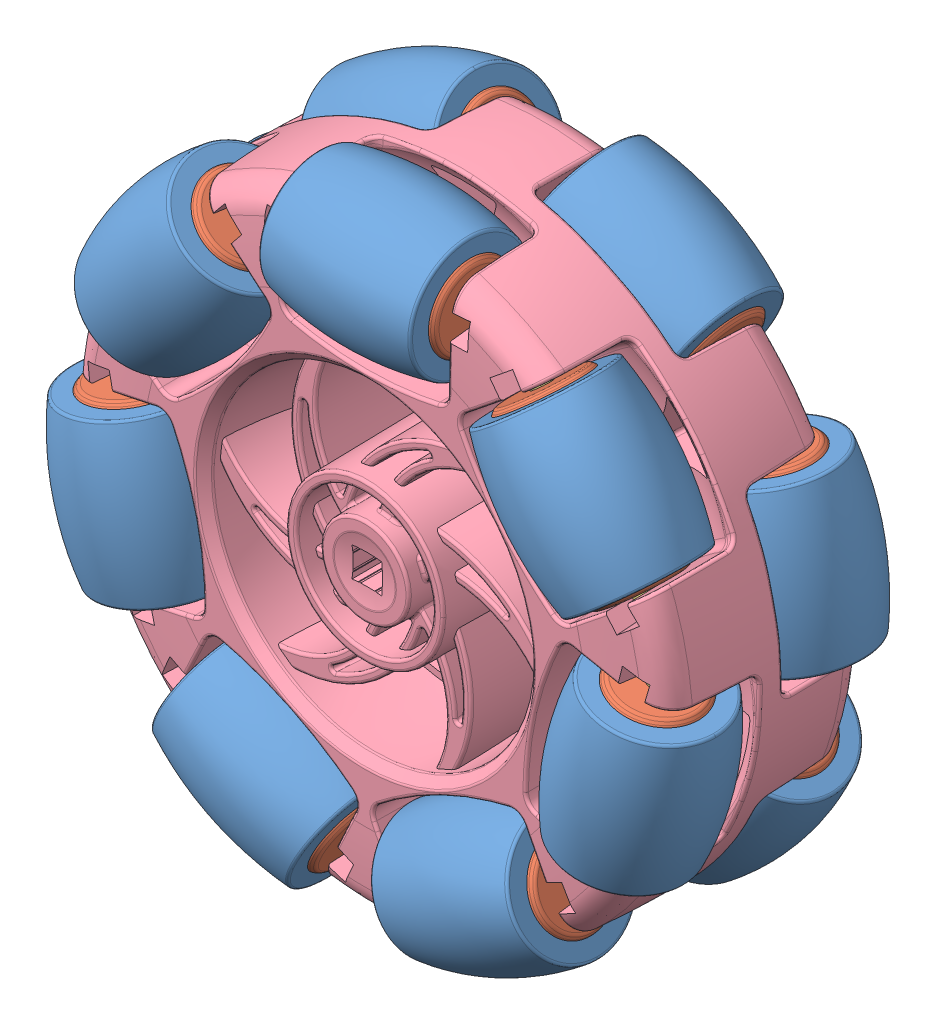
SolidWorks assembly 276-1902, configuration Default. Lengths in mm.
Overall size (73.36 73.05 31).
57 component instances, 4 part files, 0 mates.
Components (placement in the parent):
- ASM-SMALL-WHEEL_ASM-1: ASM-SMALL-WHEEL_ASM [Default] at (0 0 8) size (23 15 15)
  - SMALL-RUBBER-WHEEL-1: SMALL-RUBBER-WHEEL [Default] at origin size (16.5 15 15)
  - SMALL-HUB-1: SMALL-HUB [Default] at (0 27.5 0) size (17.5 10.2 10.2)
  - SMALL-WHEEL-AXIS-1: SMALL-WHEEL-AXIS [Default] at (0 27.5 0) x (0 1 0) z (1 0 0) size (2 2 23)
- ASM-SMALL-WHEEL_ASM-2: ASM-SMALL-WHEEL_ASM [Default] at (0 0 8) x (-0.222399 -0.974956 0) z (0 0 1) size (23 15 15)
  - SMALL-RUBBER-WHEEL-1: SMALL-RUBBER-WHEEL [Default] at origin size (16.5 15 15)
  - SMALL-HUB-1: SMALL-HUB [Default] at (0 27.5 0) size (17.5 10.2 10.2)
  - SMALL-WHEEL-AXIS-1: SMALL-WHEEL-AXIS [Default] at (0 27.5 0) x (0 1 0) z (1 0 0) size (2 2 23)
- ASM-SMALL-WHEEL_ASM-3: ASM-SMALL-WHEEL_ASM [Default] at (0 0 8) x (-0.900926 -0.433974 0) z (0 0 1) size (23 15 15)
  - SMALL-RUBBER-WHEEL-1: SMALL-RUBBER-WHEEL [Default] at origin size (16.5 15 15)
  - SMALL-HUB-1: SMALL-HUB [Default] at (0 27.5 0) size (17.5 10.2 10.2)
  - SMALL-WHEEL-AXIS-1: SMALL-WHEEL-AXIS [Default] at (0 27.5 0) x (0 1 0) z (1 0 0) size (2 2 23)
- ASM-SMALL-WHEEL_ASM-4: ASM-SMALL-WHEEL_ASM [Default] at (0 0 8) x (0.623607 -0.781738 0) z (0 0 1) size (23 15 15)
  - SMALL-RUBBER-WHEEL-1: SMALL-RUBBER-WHEEL [Default] at origin size (16.5 15 15)
  - SMALL-HUB-1: SMALL-HUB [Default] at (0 27.5 0) size (17.5 10.2 10.2)
  - SMALL-WHEEL-AXIS-1: SMALL-WHEEL-AXIS [Default] at (0 27.5 0) x (0 1 0) z (1 0 0) size (2 2 23)
- ASM-SMALL-WHEEL_ASM-5: ASM-SMALL-WHEEL_ASM [Default] at (0 -55 -8) size (23 15 15)
  - SMALL-RUBBER-WHEEL-1: SMALL-RUBBER-WHEEL [Default] at origin size (16.5 15 15)
  - SMALL-HUB-1: SMALL-HUB [Default] at (0 27.5 0) size (17.5 10.2 10.2)
  - SMALL-WHEEL-AXIS-1: SMALL-WHEEL-AXIS [Default] at (0 27.5 0) x (0 1 0) z (1 0 0) size (2 2 23)
- ASM-SMALL-WHEEL_ASM-6: ASM-SMALL-WHEEL_ASM [Default] at (43.0016 -34.2909 -8) x (0.62347 0.781847 0) z (0 0 1) size (23 15 15)
  - SMALL-RUBBER-WHEEL-1: SMALL-RUBBER-WHEEL [Default] at origin size (16.5 15 15)
  - SMALL-HUB-1: SMALL-HUB [Default] at (0 27.5 0) size (17.5 10.2 10.2)
  - SMALL-WHEEL-AXIS-1: SMALL-WHEEL-AXIS [Default] at (0 27.5 0) x (0 1 0) z (1 0 0) size (2 2 23)
- ASM-SMALL-WHEEL_ASM-7: ASM-SMALL-WHEEL_ASM [Default] at (53.6204 12.2413 -8) x (-0.22257 0.974917 0) z (0 0 1) size (23 15 15)
  - SMALL-RUBBER-WHEEL-1: SMALL-RUBBER-WHEEL [Default] at origin size (16.5 15 15)
  - SMALL-HUB-1: SMALL-HUB [Default] at (0 27.5 0) size (17.5 10.2 10.2)
  - SMALL-WHEEL-AXIS-1: SMALL-WHEEL-AXIS [Default] at (0 27.5 0) x (0 1 0) z (1 0 0) size (2 2 23)
- ASM-SMALL-WHEEL_ASM-8: ASM-SMALL-WHEEL_ASM [Default] at (23.8599 49.5551 -8) x (-0.901001 0.433816 0) z (0 0 1) size (23 15 15)
  - SMALL-RUBBER-WHEEL-1: SMALL-RUBBER-WHEEL [Default] at origin size (16.5 15 15)
  - SMALL-HUB-1: SMALL-HUB [Default] at (0 27.5 0) size (17.5 10.2 10.2)
  - SMALL-WHEEL-AXIS-1: SMALL-WHEEL-AXIS [Default] at (0 27.5 0) x (0 1 0) z (1 0 0) size (2 2 23)
- 275-OMNI-DIRECTIONAL-WHEEL-1: 275-OMNI-DIRECTIONAL-WHEEL [Default] at origin size (67.55 66.23 22.52)
- ASM-SMALL-WHEEL_ASM-9: ASM-SMALL-WHEEL_ASM [Default] at (-23.8685 49.5509 -8) x (-0.900926 -0.433974 0) z (0 0 1) size (23 15 15)
  - SMALL-RUBBER-WHEEL-1: SMALL-RUBBER-WHEEL [Default] at origin size (16.5 15 15)
  - SMALL-HUB-1: SMALL-HUB [Default] at (0 27.5 0) size (17.5 10.2 10.2)
  - SMALL-WHEEL-AXIS-1: SMALL-WHEEL-AXIS [Default] at (0 27.5 0) x (0 1 0) z (1 0 0) size (2 2 23)
- ASM-SMALL-WHEEL_ASM-10: ASM-SMALL-WHEEL_ASM [Default] at (-53.6226 12.232 -8) x (-0.222399 -0.974956 0) z (0 0 1) size (23 15 15)
  - SMALL-RUBBER-WHEEL-1: SMALL-RUBBER-WHEEL [Default] at origin size (16.5 15 15)
  - SMALL-HUB-1: SMALL-HUB [Default] at (0 27.5 0) size (17.5 10.2 10.2)
  - SMALL-WHEEL-AXIS-1: SMALL-WHEEL-AXIS [Default] at (0 27.5 0) x (0 1 0) z (1 0 0) size (2 2 23)
- ASM-SMALL-WHEEL_ASM-11: ASM-SMALL-WHEEL_ASM [Default] at (0 0 8) x (-0.901001 0.433816 0) z (0 0 1) size (23 15 15)
  - SMALL-RUBBER-WHEEL-1: SMALL-RUBBER-WHEEL [Default] at origin size (16.5 15 15)
  - SMALL-HUB-1: SMALL-HUB [Default] at (0 27.5 0) size (17.5 10.2 10.2)
  - SMALL-WHEEL-AXIS-1: SMALL-WHEEL-AXIS [Default] at (0 27.5 0) x (0 1 0) z (1 0 0) size (2 2 23)
- ASM-SMALL-WHEEL_ASM-12: ASM-SMALL-WHEEL_ASM [Default] at (0 0 8) x (-0.22257 0.974917 0) z (0 0 1) size (23 15 15)
  - SMALL-RUBBER-WHEEL-1: SMALL-RUBBER-WHEEL [Default] at origin size (16.5 15 15)
  - SMALL-HUB-1: SMALL-HUB [Default] at (0 27.5 0) size (17.5 10.2 10.2)
  - SMALL-WHEEL-AXIS-1: SMALL-WHEEL-AXIS [Default] at (0 27.5 0) x (0 1 0) z (1 0 0) size (2 2 23)
- ASM-SMALL-WHEEL_ASM-13: ASM-SMALL-WHEEL_ASM [Default] at (-42.9956 -34.2984 -8) x (0.623607 -0.781738 0) z (0 0 1) size (23 15 15)
  - SMALL-RUBBER-WHEEL-1: SMALL-RUBBER-WHEEL [Default] at origin size (16.5 15 15)
  - SMALL-HUB-1: SMALL-HUB [Default] at (0 27.5 0) size (17.5 10.2 10.2)
  - SMALL-WHEEL-AXIS-1: SMALL-WHEEL-AXIS [Default] at (0 27.5 0) x (0 1 0) z (1 0 0) size (2 2 23)
- ASM-SMALL-WHEEL_ASM-14: ASM-SMALL-WHEEL_ASM [Default] at (0 0 8) x (0.62347 0.781847 0) z (0 0 1) size (23 15 15)
  - SMALL-RUBBER-WHEEL-1: SMALL-RUBBER-WHEEL [Default] at origin size (16.5 15 15)
  - SMALL-HUB-1: SMALL-HUB [Default] at (0 27.5 0) size (17.5 10.2 10.2)
  - SMALL-WHEEL-AXIS-1: SMALL-WHEEL-AXIS [Default] at (0 27.5 0) x (0 1 0) z (1 0 0) size (2 2 23)
